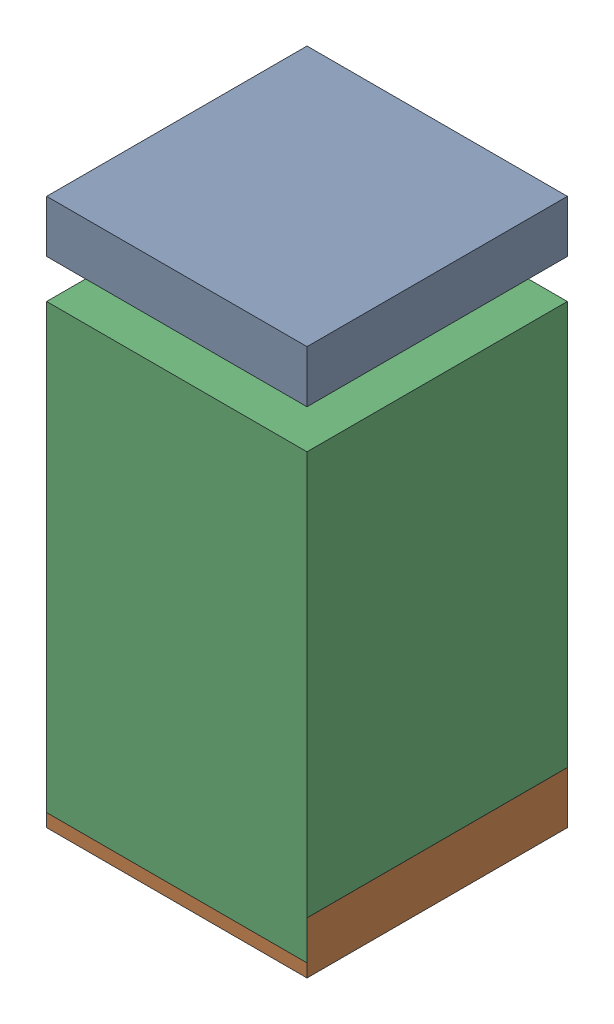
SolidWorks assembly C23, configuration Default. Lengths in mm.
Overall size (0.5 1.05 0.5).
6 component instances, 2 part files, 0 mates.
Components (placement in the parent):
- 810157360-1: 810157360 [Default] at (132.25 25.9 0) size (0.5 0.1 0.5)
  - Extruded_9-1: Extruded_9 [Default] at origin size (0.5 0.1 0.5)
- 810157360-2: 810157360 [Default] at (132.25 24.95 0) size (0.5 0.1 0.5)
  - Extruded_9-1: Extruded_9 [Default] at origin size (0.5 0.1 0.5)
- 810157104-1: 810157104 [Default] at (132.2499 25.3501 0) size (0.5 0.85 0.5)
  - Extruded_16-1: Extruded_16 [Default] at origin size (0.5 0.85 0.5)
